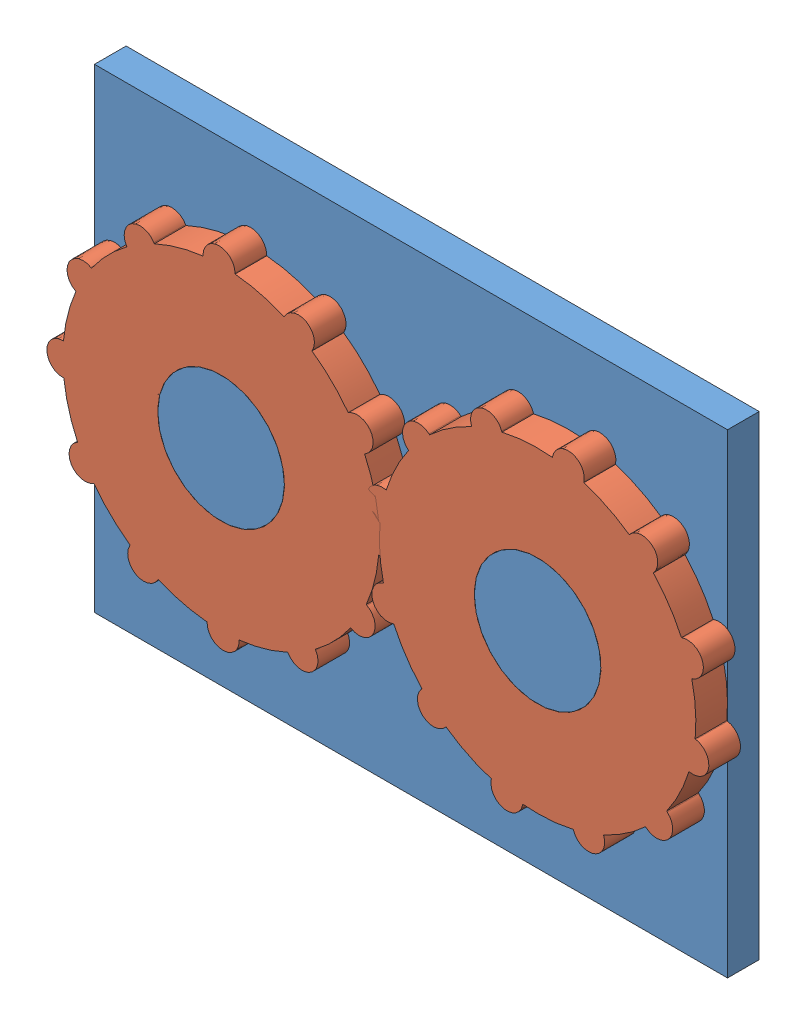
SolidWorks assembly Assem1, configuration Default. Lengths in mm.
Overall size (252.63 155.37 20).
3 component instances, 2 part files, 4 mates.
Components (placement in the parent):
- plane_d3-1: plane_d3 [Default] at origin size (200 150 20)
- gear_3d-1: gear_3d [Default] at (-51.369 -5.0309 10) x (0.872387 -0.488816 0) z (0 0 1) size (110.11 110.11 10)
- gear_3d-2: gear_3d [Default] at (48.631 -5.0309 10) x (0.752696 -0.658369 0) z (0 0 1) size (110.11 110.11 10)
Mates (geometry in assembly coordinates):
- Coincident1: coincident aligned: circle of plane_d3-1; circle of gear_3d-1
- Coincident2: coincident aligned: circle of plane_d3-1; circle of gear_3d-2
- Coincident3: coincident anti-aligned: plane of plane_d3-1 through (0 0 10) normal (0 0 1); plane of gear_3d-2 through (48.631 -5.0309 10) normal (0 0 -1)
- Coincident4: coincident anti-aligned: plane of plane_d3-1 through (0 0 10) normal (0 0 1); plane of gear_3d-1 through (-51.369 -5.0309 10) normal (0 0 -1)
